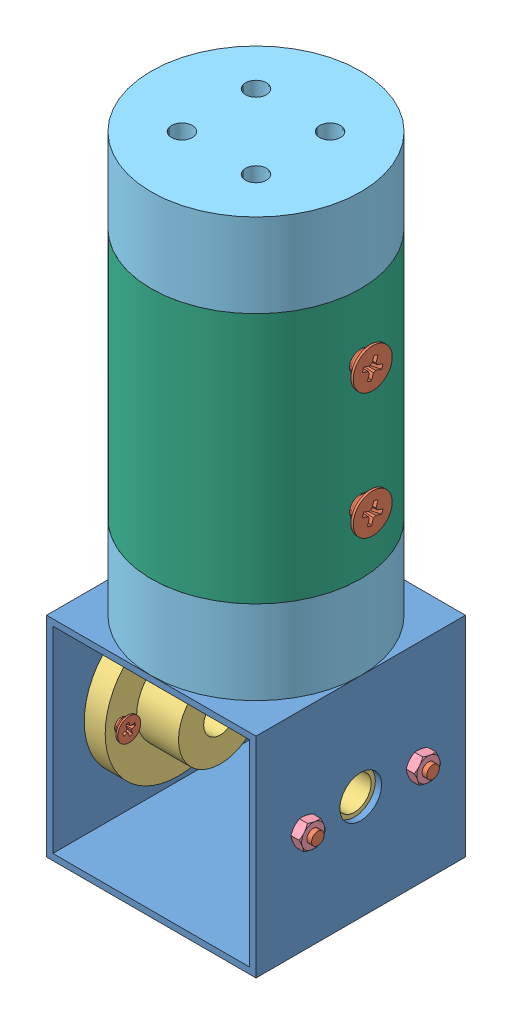
SolidWorks assembly Elo4-Assembly, configuration Valor predeterminado. Lengths in mm.
Overall size (57.04 150 50).
23 component instances, 6 part files, 14 mates.
Components (placement in the parent):
- Caixa Alumínio 2-1: Caixa Alumínio 2 [Valor predeterminado] at (4.0801 -5.0983 61.2615) size (57.04 61.26 50)
  - Caixa Aluminio 1-1: Caixa Aluminio 1 [Valor predeterminado] at (-10.3148 1.616 25) size (50 50 50)
  - countersunk flat head cross recess screw_iso-1: countersunk flat head cross recess screw_iso [ISO 7046-1 - M3 x 12 - Z - 12N] at (-26.8335 1.616 63.75) x (-1 0 0) z (0 -0.954727 -0.297484) size (12 5.5 5.5)
  - countersunk flat head cross recess screw_iso-2: countersunk flat head cross recess screw_iso [ISO 7046-1 - M5 x 16 - Z - 16N] at (-1.476 21.8775 41.1612) x (0 1 0) z (0.529882 0 -0.848071) size (16 9.3 9.3)
  - Bucha 8 mm-1: Bucha 8 mm [Valor predeterminado] at (-33.8148 1.616 50) x (0 -1 0) z (0 0 1) size (35 15 35)
  - Bucha 8 mm-2: Bucha 8 mm [Valor predeterminado] at (13.1852 1.616 50) x (0 1 0) z (0 0 1) size (35 15 35)
  - countersunk flat head cross recess screw_iso-3: countersunk flat head cross recess screw_iso [ISO 7046-1 - M3 x 12 - Z - 12N] at (6.2038 1.616 36.25) x (1 0 0) z (0 -0.08962 0.995976) size (12 5.5 5.5)
  - countersunk flat head cross recess screw_iso-4: countersunk flat head cross recess screw_iso [ISO 7046-1 - M3 x 12 - Z - 12N] at (6.2038 1.616 63.75) x (1 0 0) z (0 -0.08962 0.995976) size (12 5.5 5.5)
  - countersunk flat head cross recess screw_iso-5: countersunk flat head cross recess screw_iso [ISO 7046-1 - M3 x 12 - Z - 12N] at (-26.8335 1.616 36.25) x (-1 0 0) z (0 -0.954727 -0.297484) size (12 5.5 5.5)
  - countersunk flat head cross recess screw_iso-6: countersunk flat head cross recess screw_iso [ISO 7046-1 - M5 x 16 - Z - 16N] at (-19.1537 21.8775 58.8388) x (0 1 0) z (0.529882 0 -0.848071) size (16 9.3 9.3)
  - countersunk flat head cross recess screw_iso-7: countersunk flat head cross recess screw_iso [ISO 7046-1 - M5 x 16 - Z - 16N] at (-1.476 21.8775 58.8388) x (0 1 0) z (0.529882 0 -0.848071) size (16 9.3 9.3)
  - countersunk flat head cross recess screw_iso-8: countersunk flat head cross recess screw_iso [ISO 7046-1 - M5 x 16 - Z - 16N] at (-19.1537 21.8775 41.1612) x (0 1 0) z (0.529882 0 -0.848071) size (16 9.3 9.3)
  - hex nut style 1 gradeab_iso-1: hex nut style 1 gradeab_iso [ISO - 4032 - M3 - D - N] at (-35.3148 1.616 63.75) x (0 0.352257 0.935903) z (1 0 0) size (5.5 6.35 2.4)
  - hex nut style 1 gradeab_iso-2: hex nut style 1 gradeab_iso [ISO - 4032 - M3 - D - N] at (-35.3148 1.616 36.25) x (0 0.352257 0.935903) z (1 0 0) size (5.5 6.35 2.4)
  - hex nut style 1 gradeab_iso-3: hex nut style 1 gradeab_iso [ISO - 4032 - M3 - D - N] at (14.6852 1.616 63.75) x (0 -0.352257 0.935903) z (-1 0 0) size (5.5 6.35 2.4)
  - hex nut style 1 gradeab_iso-4: hex nut style 1 gradeab_iso [ISO - 4032 - M3 - D - N] at (14.6852 1.616 36.25) x (0 -0.352257 0.935903) z (-1 0 0) size (5.5 6.35 2.4)
- Conector Nylon-1: Conector Nylon [Valor predeterminado] at (-6.2348 41.5177 111.2615) x (0 0 -1) z (1 0 0) size (50 50 50)
- Conector PVC 3-4-1: Conector PVC 3-4 [Valor predeterminado] at (-6.2348 41.5177 111.2615) x (0 0 1) z (-1 0 0) size (50 60 50)
- Conector Nylon-2: Conector Nylon [Valor predeterminado] at (-6.2348 101.5177 111.2615) x (0 0 -1) z (-1 0 0) size (50 50 50)
- countersunk flat head cross recess screw_iso-1: countersunk flat head cross recess screw_iso [ISO 7046-1 - M5 x 10 - Z - 10N] at (21.6252 56.5177 111.2615) x (-1 0 0) z (0 0.330714 0.943731) size (10 9.3 9.3)
- countersunk flat head cross recess screw_iso-2: countersunk flat head cross recess screw_iso [ISO 7046-1 - M5 x 10 - Z - 10N] at (21.6252 86.5177 111.2615) x (-1 0 0) z (0 0.330714 0.943731) size (10 9.3 9.3)
- countersunk flat head cross recess screw_iso-4: countersunk flat head cross recess screw_iso [ISO 7046-1 - M5 x 10 - Z - 10N] at (-34.0948 86.5177 111.2615) x (1 0 0) z (0 -0.745936 -0.666017) size (10 9.3 9.3)
- countersunk flat head cross recess screw_iso-5: countersunk flat head cross recess screw_iso [ISO 7046-1 - M5 x 10 - Z - 10N] at (-34.0948 56.5177 111.2615) x (1 0 0) z (0 -0.745936 -0.666017) size (10 9.3 9.3)
Mates (geometry in assembly coordinates):
- Coincident1: coincident: circle of Caixa Alumínio 2-1/Caixa Aluminio 1-1; circle of Conector Nylon-1
- Coincident2: coincident: circle of Caixa Alumínio 2-1/Caixa Aluminio 1-1; circle of Conector Nylon-1
- Concentric1: concentric: cylinder of Conector Nylon-1 through (19.5652 56.5177 111.2615) axis (1 0 0) radius 2.1; cylinder of Conector PVC 3-4-1 through (18.7652 56.5177 111.2615) axis (-1 0 0) radius 2.5
- Concentric2: concentric: cylinder of Conector Nylon-1 through (-6.2348 71.5187 111.2615) axis (0 -1 0) radius 25; cylinder of Conector PVC 3-4-1 through (-6.2348 101.5177 111.2615) axis (0 -1 0) radius 25
- Concentric3: concentric: cylinder of Conector PVC 3-4-1 through (-6.2348 101.5177 111.2615) axis (0 -1 0) radius 25; cylinder of Conector Nylon-2 through (-6.2348 71.5177 111.2615) axis (0 1 0) radius 22
- Concentric4: concentric: cylinder of Conector PVC 3-4-1 through (18.7652 86.5177 111.2615) axis (-1 0 0) radius 2.5; cylinder of Conector Nylon-2 through (19.5652 86.5177 111.2615) axis (1 0 0) radius 2.1
- Coincident3: coincident: cylinder of Conector PVC 3-4-1 through (18.7652 56.5177 111.2615) axis (-1 0 0) radius 2.5; circle of countersunk flat head cross recess screw_iso-1
- Distance1: distance = 2.86 mm: plane of countersunk flat head cross recess screw_iso-1 through (21.6252 56.5177 111.2615) normal (1 0 0); plane of Caixa Alumínio 2-1/Caixa Aluminio 1-1 through (18.7652 -28.4823 136.2615) normal (1 0 0)
- Concentric5: concentric: cylinder of Conector PVC 3-4-1 through (18.7652 86.5177 111.2615) axis (-1 0 0) radius 2.5; circle of countersunk flat head cross recess screw_iso-2
- Coincident6: coincident: plane of countersunk flat head cross recess screw_iso-1 through (21.6252 56.5177 111.2615) normal (1 0 0); plane of countersunk flat head cross recess screw_iso-2 through (21.6252 86.5177 111.2615) normal (1 0 0)
- Concentric6: concentric: circle of countersunk flat head cross recess screw_iso-4; cylinder of Conector PVC 3-4-1 through (18.7652 86.5177 111.2615) axis (-1 0 0) radius 2.5
- Distance2: distance = 2.86 mm: plane of countersunk flat head cross recess screw_iso-4 through (-34.0948 86.5177 111.2615) normal (-1 0 0); plane of Caixa Alumínio 2-1/Caixa Aluminio 1-1 through (-31.2348 -28.4823 136.2615) normal (-1 0 0)
- Coincident8: coincident: plane of countersunk flat head cross recess screw_iso-4 through (-34.0948 86.5177 111.2615) normal (-1 0 0); plane of countersunk flat head cross recess screw_iso-5 through (-34.0948 56.5177 111.2615) normal (-1 0 0)
- Coincident9: coincident: cylinder of Conector PVC 3-4-1 through (18.7652 56.5177 111.2615) axis (-1 0 0) radius 2.5; circle of countersunk flat head cross recess screw_iso-5
